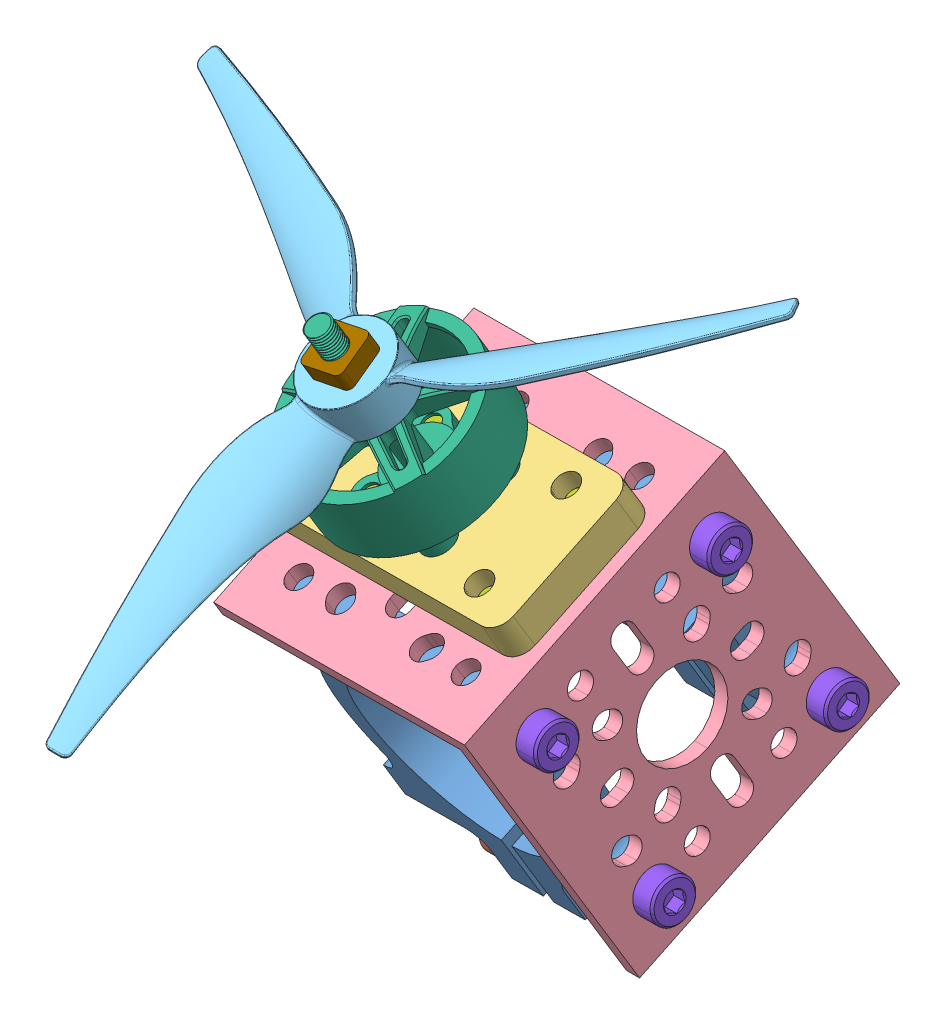
SolidWorks assembly push_mechanism, configuration Default. Lengths in mm.
Overall size (110.11 110.42 117.37).
25 component instances, 9 part files, 46 mates.
Components (placement in the parent):
- 1401-0043-0032 assembly-1: 1401-0043-0032 assembly [Default] at (33.1136 3.9504 78.0663) x (0.988236 0.111473 0.104709) z (-0.147897 0.87089 0.468698) size (43.01 8.04 47.02)
  - 1401-0043-0032 assembly.STEP-1: 1401-0043-0032 assembly.STEP [Default] at origin size (43.01 8.04 47.02)
    - 1401-0043-0032.STEP-1: 1401-0043-0032.STEP [Default] at (0.7931 12.12 -4.4026) size (43.01 8 46.5)
    - 2800-0004-0014_90128A207.STEP-1: 2800-0004-0014_90128A207.STEP [Default] at (7.7931 12.12 -28.4026) x (0 0.161804 -0.986823) z (1 0 0) size (7 7 18.01)
- 1401-0043-0032 assembly-2: 1401-0043-0032 assembly [Default] at (31.8674 -11.367 106.1345) x (0.988236 0.111473 0.104709) z (-0.147897 0.87089 0.468698) size (43.01 8.04 47.02)
  - 1401-0043-0032 assembly.STEP-1: 1401-0043-0032 assembly.STEP [Default] at origin size (43.01 8.04 47.02)
    - 1401-0043-0032.STEP-1: 1401-0043-0032.STEP [Default] at (0.7931 12.12 -4.4026) size (43.01 8 46.5)
    - 2800-0004-0014_90128A207.STEP-1: 2800-0004-0014_90128A207.STEP [Default] at (7.7931 12.12 -28.4026) x (0 0.161804 -0.986823) z (1 0 0) size (7 7 18.01)
- motor_mounting_board-1: motor_mounting_board [Default] at (32.9376 22.3694 90.2927) x (0.988236 0.111473 0.104709) z (-0.147897 0.87089 0.468698) size (48 25 6)
- 1113-0001-0048-1: 1113-0001-0048 [默认] at (30.2829 5.5834 110.6173) x (0.988236 0.111473 0.104709) z (-0.147897 0.87089 0.468698) size (48 48 48)
- Gemfan Propeller 51466-1: Gemfan Propeller 51466 [Default] at (26.3444 45.7673 105.0097) x (0.988308 0.147897 0.037051) z (0.037051 -0.468698 0.882581) size (106.5 9.65 92.55)
- T-Motor F80Pro-1: T-Motor F80Pro [Default] at (29.709 25.9546 94.3469) x (0.671251 -0.259648 0.694266) z (-0.147897 0.87089 0.468698) size (29.02 29.02 33.9)
- 2802-0004-0008-2: 2802-0004-0008 [Default] at (47.0432 13.1098 97.2274) x (0.95883 0.242428 -0.147897) z (0.147897 -0.87089 -0.468698) size (7.6 7.6 10.21)
- 2802-0004-0008-3: 2802-0004-0008 [Default] at (15.4196 9.5426 93.8767) x (0.95883 0.242428 -0.147897) z (0.147897 -0.87089 -0.468698) size (7.6 7.6 10.21)
- 2802-0004-0008-4: 2802-0004-0008 [Default] at (16.0427 17.2014 79.8426) x (0.95883 0.242428 -0.147897) z (0.147897 -0.87089 -0.468698) size (7.6 7.6 10.21)
- 2802-0004-0008-5: 2802-0004-0008 [Default] at (47.6663 20.7685 83.1933) x (0.965672 0.024834 0.258574) z (0.147897 -0.87089 -0.468698) size (7.6 7.6 10.21)
- 2800-0004-0010-2: 2800-0004-0010 [Default] at (46.4894 21.501 74.4201) x (-0.090735 -0.123804 0.98815) z (-0.988236 -0.111473 -0.104709) size (7 7 14.01)
- 2800-0004-0010-3: 2800-0004-0010 [Default] at (51.2221 -6.3675 59.4218) x (-0.090735 -0.123804 0.98815) z (-0.988236 -0.111473 -0.104709) size (7 7 14.01)
- 2800-0004-0010-4: 2800-0004-0010 [Default] at (45.2432 6.1835 102.4883) x (-0.090735 -0.123804 0.98815) z (-0.988236 -0.111473 -0.104709) size (7 7 14.01)
- 2800-0004-0010-5: 2800-0004-0010 [Default] at (49.9759 -21.6849 87.49) x (-0.090735 -0.123804 0.98815) z (-0.988236 -0.111473 -0.104709) size (7 7 14.01)
- 2802-0004-0008-9: 2802-0004-0008 [Default] at (36.6584 22.5871 86.3684) x (0.594903 -0.300249 0.745615) z (0.147897 -0.87089 -0.468698) size (7.6 7.6 10.21)
- 2802-0004-0008-10: 2802-0004-0008 [Default] at (25.4778 21.3259 85.1838) x (0.594903 -0.300249 0.745615) z (0.147897 -0.87089 -0.468698) size (7.6 7.6 10.21)
- 2802-0004-0008-11: 2802-0004-0008 [Default] at (25.0372 15.9104 95.1074) x (0.95883 0.242428 -0.147897) z (0.147897 -0.87089 -0.468698) size (7.6 7.6 10.21)
- 2802-0004-0008-12: 2802-0004-0008 [Default] at (36.2179 17.1716 96.292) x (0.95883 0.242428 -0.147897) z (0.147897 -0.87089 -0.468698) size (7.6 7.6 10.21)
- 2803-0007-0007-2: 2803-0007-0007 [默认] at (25.8415 48.7284 106.6033) x (0.98334 0.18013 -0.024408) z (0.105683 -0.45728 0.883021) size (7 3.01 7)
Mates (geometry in assembly coordinates):
- Coincident1: coincident anti-aligned: circle of 1120-0001-0048-1; circle of 1401-0043-0032 assembly-1/1401-0043-0032 assembly.STEP-1/1401-0043-0032.STEP-1
- Coincident2: coincident aligned: circle of 1120-0001-0048-1; circle of 1401-0043-0032 assembly-1/1401-0043-0032 assembly.STEP-1/1401-0043-0032.STEP-1
- Coincident3: coincident anti-aligned: circle of 1120-0001-0048-1; circle of 1401-0043-0032 assembly-2/1401-0043-0032 assembly.STEP-1/1401-0043-0032.STEP-1
- Coincident4: coincident aligned: circle of 1120-0001-0048-1; circle of 1401-0043-0032 assembly-2/1401-0043-0032 assembly.STEP-1/1401-0043-0032.STEP-1
- Concentric1: concentric anti-aligned: cylinder of 1120-0001-0048-1 through (-11.0793 -7.4597 62) axis (0 0 1) radius 2; cylinder of motor_mounting_board-1 through (-11.0793 -7.4597 78) axis (0 0 -1) radius 2.05
- Concentric2: concentric anti-aligned: cylinder of 1120-0001-0048-1 through (-11.0793 8.5403 62) axis (0 0 1) radius 2; cylinder of motor_mounting_board-1 through (-11.0793 8.5403 78) axis (0 0 -1) radius 2.05
- Coincident5: coincident anti-aligned: plane of 1120-0001-0048-1 through (4.9207 24.5403 72) normal (0 0 1); plane of motor_mounting_board-1 through (32.9376 22.3694 90.2927) normal (0.147897 -0.87089 -0.468698)
- Coincident6: coincident anti-aligned: circle of 1401-0043-0032 assembly-1/1401-0043-0032 assembly.STEP-1/1401-0043-0032.STEP-1; circle of 1113-0001-0048-1
- Coincident7: coincident aligned: circle of 1401-0043-0032 assembly-2/1401-0043-0032 assembly.STEP-1/1401-0043-0032.STEP-1; circle of 1113-0001-0048-1
- Coincident8: coincident anti-aligned: circle of 1401-0043-0032 assembly-2/1401-0043-0032 assembly.STEP-1/1401-0043-0032.STEP-1; circle of 1113-0001-0048-1
- Coincident9: coincident aligned: circle of 1401-0043-0032 assembly-1/1401-0043-0032 assembly.STEP-1/1401-0043-0032.STEP-1; circle of 1113-0001-0048-1
- Concentric3: concentric anti-aligned: cylinder of motor_mounting_board-1 through (45.1353 24.3442 103.2736) axis (0.147897 -0.87089 -0.468698) radius 2.05; cylinder of 1113-0001-0048-1 through (47.827 8.4941 94.7433) axis (-0.147897 0.87089 0.468698) radius 2
- Concentric4: concentric anti-aligned: cylinder of motor_mounting_board-1 through (45.7584 32.003 89.2395) axis (0.147897 -0.87089 -0.468698) radius 2.05; cylinder of 1113-0001-0048-1 through (48.4501 16.1528 80.7092) axis (-0.147897 0.87089 0.468698) radius 2
- Coincident11: coincident anti-aligned: circle of motor_mounting_board-1; circle of T-Motor F100 2810 KV1350 5-6S Motor-1/T-Motor F100 2810 KV1350 5-6S Motor.STEP-1/T-Motor F100 2810 KV1350 Stator.STEP-1
- Concentric5: concentric anti-aligned: cylinder of motor_mounting_board-1 through (35.4457 29.7284 90.2117) axis (0.147897 -0.87089 -0.468698) radius 1.55; cylinder of T-Motor F80Pro-1 through (35.5196 29.293 89.9774) axis (-0.147897 0.87089 0.468698) radius 1.5
- Concentric6: concentric anti-aligned: cylinder of motor_mounting_board-1 through (35.0051 24.3129 100.1353) axis (0.147897 -0.87089 -0.468698) radius 1.55; cylinder of T-Motor F80Pro-1 through (35.079 23.8774 99.901) axis (-0.147897 0.87089 0.468698) radius 1.5
- Coincident12: coincident anti-aligned: plane of motor_mounting_board-1 through (32.0502 27.5947 93.1049) normal (-0.147897 0.87089 0.468698); plane of T-Motor F80Pro-1 through (29.6351 26.39 94.5812) normal (0.147897 -0.87089 -0.468698)
- Concentric7: concentric aligned: cylinder of Gemfan Propeller 51466-1 through (25.8415 48.7284 106.6033) axis (0.147897 -0.87089 -0.468698) radius 2.5; cylinder of T-Motor F80Pro-1 through (27.2057 40.6951 102.28) axis (0.147897 -0.87089 -0.468698) radius 1.9635
- Coincident13: coincident anti-aligned: plane of Gemfan Propeller 51466-1 through (26.8472 42.8063 103.4162) normal (0.147897 -0.87089 -0.468698); plane of T-Motor F80Pro-1 through (27.435 43.144 102.9741) normal (-0.147897 0.87089 0.468698)
- Concentric81: concentric anti-aligned: cylinder of 1113-0001-0048-1 through (47.827 8.4941 94.7433) axis (-0.147897 0.87089 0.468698) radius 2; cylinder of 2802-0004-0008-2 through (47.0432 13.1098 97.2274) axis (0.147897 -0.87089 -0.468698) radius 3.8
- Coincident141: coincident anti-aligned: plane of 1113-0001-0048-1 through (10.9052 26.163 66.2638) normal (0.147897 -0.87089 -0.468698); plane of 2802-0004-0008-2 through (45.7966 16.6503 94.9492) normal (-0.147897 0.87089 0.468698)
- Concentric91: concentric anti-aligned: cylinder of 1113-0001-0048-1 through (16.2035 4.9269 91.3926) axis (-0.147897 0.87089 0.468698) radius 2; cylinder of 2802-0004-0008-3 through (15.4196 9.5426 93.8767) axis (0.147897 -0.87089 -0.468698) radius 3.8
- Coincident151: coincident anti-aligned: plane of 1113-0001-0048-1 through (10.9052 26.163 66.2638) normal (0.147897 -0.87089 -0.468698); plane of 2802-0004-0008-3 through (14.173 13.0832 91.5985) normal (-0.147897 0.87089 0.468698)
- Concentric101: concentric anti-aligned: cylinder of 1113-0001-0048-1 through (16.8266 12.5857 77.3585) axis (-0.147897 0.87089 0.468698) radius 2; cylinder of 2802-0004-0008-4 through (16.0427 17.2014 79.8426) axis (0.147897 -0.87089 -0.468698) radius 3.8
- Coincident161: coincident anti-aligned: plane of 1113-0001-0048-1 through (10.9052 26.163 66.2638) normal (0.147897 -0.87089 -0.468698); plane of 2802-0004-0008-4 through (14.7961 20.7419 77.5644) normal (-0.147897 0.87089 0.468698)
- Concentric111: concentric anti-aligned: cylinder of 1113-0001-0048-1 through (48.4501 16.1528 80.7092) axis (-0.147897 0.87089 0.468698) radius 2; cylinder of 2802-0004-0008-5 through (47.6663 20.7685 83.1933) axis (0.147897 -0.87089 -0.468698) radius 3.8
- Coincident171: coincident anti-aligned: plane of 1113-0001-0048-1 through (10.9052 26.163 66.2638) normal (0.147897 -0.87089 -0.468698); plane of 2802-0004-0008-5 through (48.1524 24.5497 81.0147) normal (-0.147897 0.87089 0.468698)
- Concentric121: concentric anti-aligned: cylinder of 1113-0001-0048-1 through (46.4894 21.501 74.4201) axis (0.988236 0.111473 0.104709) radius 2; cone of 2800-0004-0010-2 through (56.7177 22.6547 75.5039) axis (-0.988236 -0.111473 -0.104709)
- Coincident181: coincident anti-aligned: plane of 1113-0001-0048-1 through (62.5992 -8.3905 49.7023) normal (0.988236 0.111473 0.104709); plane of 2800-0004-0010-2 through (56.3718 22.6157 75.4672) normal (-0.988236 -0.111473 -0.104709)
- Concentric131: concentric anti-aligned: cylinder of 1113-0001-0048-1 through (51.2221 -6.3675 59.4218) axis (0.988236 0.111473 0.104709) radius 2; cone of 2800-0004-0010-3 through (61.4504 -5.2137 60.5056) axis (-0.988236 -0.111473 -0.104709)
- Coincident191: coincident anti-aligned: plane of 1113-0001-0048-1 through (62.5992 -8.3905 49.7023) normal (0.988236 0.111473 0.104709); plane of 2800-0004-0010-3 through (61.1045 -5.2528 60.4689) normal (-0.988236 -0.111473 -0.104709)
- Concentric141: concentric anti-aligned: cylinder of 1113-0001-0048-1 through (45.2432 6.1835 102.4883) axis (0.988236 0.111473 0.104709) radius 2; cone of 2800-0004-0010-4 through (55.4715 7.3373 103.5721) axis (-0.988236 -0.111473 -0.104709)
- Coincident201: coincident anti-aligned: plane of 1113-0001-0048-1 through (62.5992 -8.3905 49.7023) normal (0.988236 0.111473 0.104709); plane of 2800-0004-0010-4 through (55.1256 7.2983 103.5354) normal (-0.988236 -0.111473 -0.104709)
- Concentric151: concentric anti-aligned: cylinder of 1113-0001-0048-1 through (49.9759 -21.6849 87.49) axis (0.988236 0.111473 0.104709) radius 2; cone of 2800-0004-0010-5 through (60.2042 -20.5312 88.5737) axis (-0.988236 -0.111473 -0.104709)
- Coincident211: coincident anti-aligned: plane of 1113-0001-0048-1 through (62.5992 -8.3905 49.7023) normal (0.988236 0.111473 0.104709); plane of 2800-0004-0010-5 through (59.8583 -20.5702 88.5371) normal (-0.988236 -0.111473 -0.104709)
- Concentric161: concentric aligned: cylinder of motor_mounting_board-1 through (35.4457 29.7284 90.2117) axis (0.147897 -0.87089 -0.468698) radius 1.55; cylinder of 2802-0004-0008-9 through (36.6584 22.5871 86.3684) axis (0.147897 -0.87089 -0.468698) radius 3.8
- Coincident221: coincident anti-aligned: plane of motor_mounting_board-1 through (32.9376 22.3694 90.2927) normal (0.147897 -0.87089 -0.468698); plane of 2802-0004-0008-9 through (39.3354 25.9817 85.5995) normal (-0.147897 0.87089 0.468698)
- Concentric171: concentric aligned: cylinder of motor_mounting_board-1 through (24.2651 28.4672 89.0271) axis (0.147897 -0.87089 -0.468698) radius 1.55; cylinder of 2802-0004-0008-10 through (25.4778 21.3259 85.1838) axis (0.147897 -0.87089 -0.468698) radius 3.8
- Coincident231: coincident anti-aligned: plane of motor_mounting_board-1 through (32.9376 22.3694 90.2927) normal (0.147897 -0.87089 -0.468698); plane of 2802-0004-0008-10 through (28.1547 24.7205 84.4149) normal (-0.147897 0.87089 0.468698)
- Concentric181: concentric aligned: cylinder of motor_mounting_board-1 through (23.8245 23.0517 98.9507) axis (0.147897 -0.87089 -0.468698) radius 1.55; cylinder of 2802-0004-0008-11 through (25.0372 15.9104 95.1074) axis (0.147897 -0.87089 -0.468698) radius 3.8
- Coincident241: coincident anti-aligned: plane of motor_mounting_board-1 through (32.9376 22.3694 90.2927) normal (0.147897 -0.87089 -0.468698); plane of 2802-0004-0008-11 through (23.7906 19.451 92.8291) normal (-0.147897 0.87089 0.468698)
- Concentric191: concentric aligned: cylinder of motor_mounting_board-1 through (35.0051 24.3129 100.1353) axis (0.147897 -0.87089 -0.468698) radius 1.55; cylinder of 2802-0004-0008-12 through (36.2179 17.1716 96.292) axis (0.147897 -0.87089 -0.468698) radius 3.8
- Coincident251: coincident anti-aligned: plane of motor_mounting_board-1 through (32.9376 22.3694 90.2927) normal (0.147897 -0.87089 -0.468698); plane of 2802-0004-0008-12 through (34.9713 20.7121 94.0138) normal (-0.147897 0.87089 0.468698)
- Coincident26: coincident anti-aligned: plane of 1113-0001-0048-1 through (55.5001 33.4122 72.1998) normal (-0.147897 0.87089 0.468698); plane of 2802-0004-0008-10 through (27.058 22.1041 84.2364) normal (0.147897 -0.87089 -0.468698)
- Concentric201: concentric anti-aligned: cone of Gemfan Propeller 51466-1 through (25.9155 48.2929 106.369) axis (0.147897 -0.87089 -0.468698); cone of 2803-0007-0007-2 through (25.8415 48.7284 106.6033) axis (-0.147897 0.87089 0.468698)
- Coincident271: coincident anti-aligned: plane of Gemfan Propeller 51466-1 through (25.8415 48.7284 106.6033) normal (-0.147897 0.87089 0.468698); plane of 2803-0007-0007-2 through (25.8415 48.7284 106.6033) normal (0.147897 -0.87089 -0.468698)
